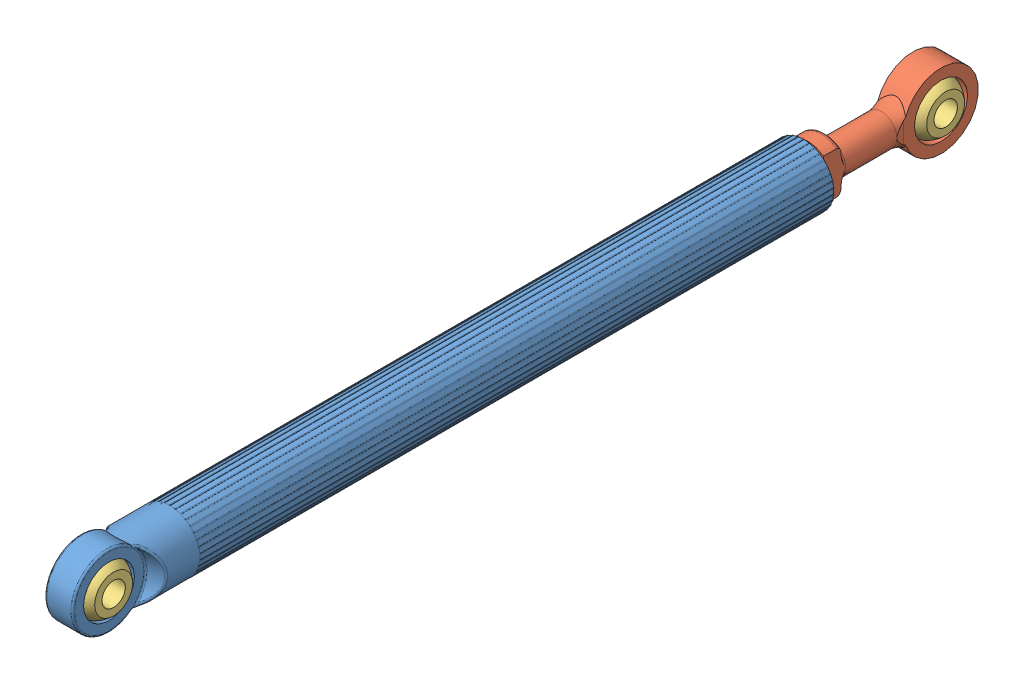
SolidWorks assembly Penny Giles Potentiometer, configuration Default. Lengths in mm.
Overall size (13.67 16 194.02).
4 component instances, 3 part files, 11 mates.
Components (placement in the parent):
- Penny Giles Potentiometer Body-1: Penny Giles Potentiometer Body [Default] at (0 0 -164) size (13.67 15.51 159.6)
- Penny Giles Potentiometer Top-1: Penny Giles Potentiometer Top [Default] at (0 0 3.402) x (1 0 0) z (0 0 -1) size (9.08 16 155.76)
- M5 Spherical-1: M5 Spherical [Default] at (0 0 -178.268) x (0 1 0) z (-1 0 0) size (11.4 11.4 8)
- M5 Spherical-2: M5 Spherical [Default] x (0 1 0) z (-1 0 0) size (11.4 11.4 8)
Mates (geometry in assembly coordinates):
- Coincident1: coincident aligned: plane of Penny Giles Potentiometer Body-1 through (0 0 -164) normal (1 0 0); plane of assembly through (0 0 0) normal (1 0 0)
- Coincident2: coincident aligned: plane of Penny Giles Potentiometer Body-1 through (0 0 -164) normal (0 1 0); plane of assembly through (0 0 0) normal (0 1 0)
- Concentric1: concentric: cylinder of Penny Giles Potentiometer Body-1 through (-3 0 0) axis (1 0 0) radius 5.4544; point of assembly
- Concentric2: concentric anti-aligned: cylinder of Penny Giles Potentiometer Body-1 through (0 0 -14) axis (0 0 -1) radius 2; cylinder of Penny Giles Potentiometer Top-1 through (0 0 -152.768) axis (0 0 1) radius 2
- Coincident4: coincident anti-aligned: plane of Penny Giles Potentiometer Top-1 through (0 0 3.402) normal (0 -1 0); plane of assembly through (0 0 0) normal (0 1 0)
- LimitDistance1: limit distance = 0.918 mm anti-aligned: plane of Penny Giles Potentiometer Body-1 through (-6.8364 -8.1394 -151.85) normal (0 0 -1); plane of Penny Giles Potentiometer Top-1 through (0 0 -152.768) normal (0 0 1)
- Concentric3: concentric anti-aligned: cylinder of Penny Giles Potentiometer Top-1 through (-5 0 -178.268) axis (1 0 0) radius 5.7; cylinder of M5 Spherical-1 through (6 0 -178.268) axis (-1 0 0) radius 2.5
- Concentric5: concentric: cylinder of M5 Spherical-2 through (6 0 0) axis (-1 0 0) radius 2.5; point of assembly
- Parallel1: parallel anti-aligned: cylinder of Penny Giles Potentiometer Body-1 through (-3 0 0) axis (1 0 0) radius 5.4544; cylinder of M5 Spherical-2 through (6 0 0) axis (-1 0 0) radius 2.5
- Coincident7: coincident anti-aligned: line of Penny Giles Potentiometer Top-1 through (0 0 84.302) axis (0 0 -1); line of M5 Spherical-2 through (0 0 -50) axis (0 0 1)
- Coincident8: coincident anti-aligned: line of Penny Giles Potentiometer Top-1 through (0 0 84.302) axis (0 0 -1); line of M5 Spherical-1 through (0 0 -228.268) axis (0 0 1)
